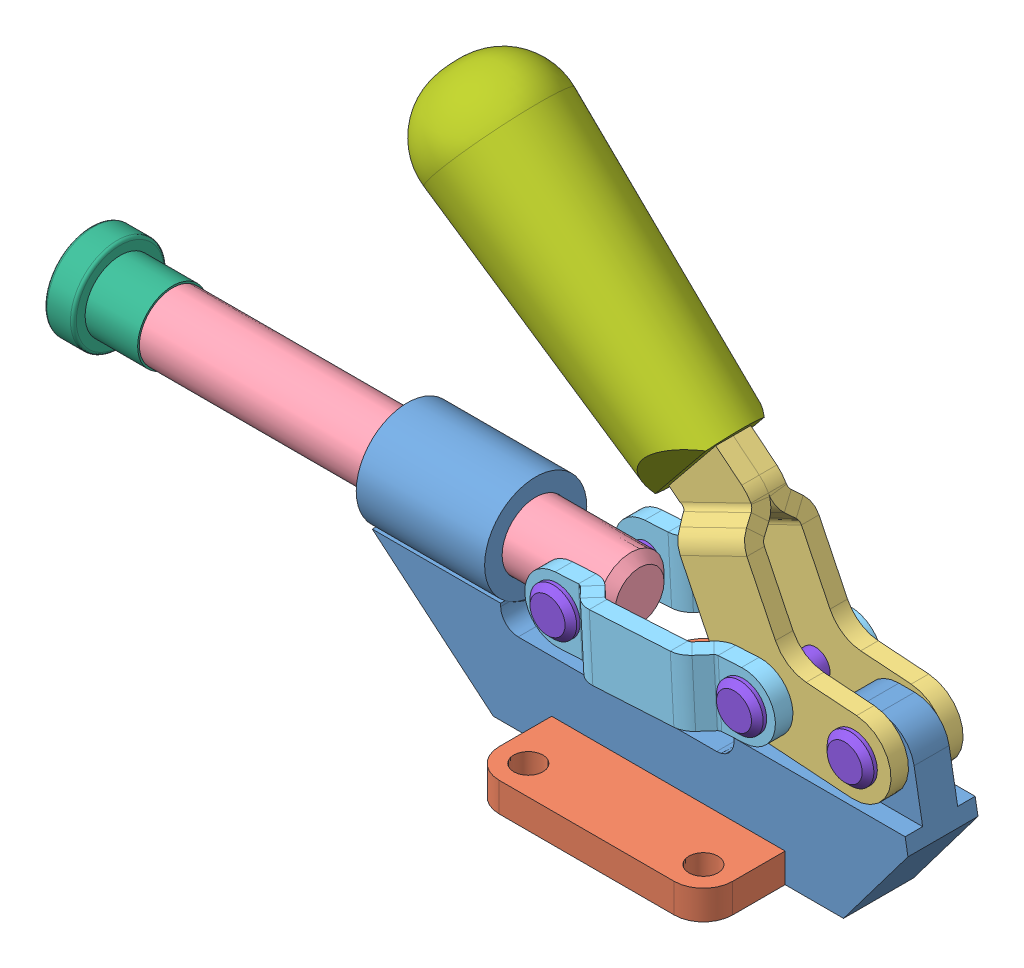
SolidWorks assembly Assem1, configuration Default. Lengths in mm.
Overall size (147.26 95.64 40).
11 component instances, 8 part files, 24 mates.
Components (placement in the parent):
- Part1-1: Part1 [Default] at origin size (91.78 33.15 17.5)
- Part6-1: Part6 [Default] at (0 5 0) size (40 5 40)
- Part2-1: Part2 [Default] at (31.9743 25.058 0) x (-0.997513 0.070487 0) z (-0.070487 -0.997513 0) size (83.44 12.35 63.32)
- Part5-1: Part5 [Default] at (-10.936 24.4 0) x (0 -1 0) z (0 0 -1) size (11.4 90 11.4)
- Part3-1: Part3 [Default] at (0.0391 25.2929 9.35) x (0.998442 0.055804 0) z (0.055804 -0.998442 0) size (43 6.17 11)
- Part3-2: Part3 [Default] at (0.0391 25.2929 -9.35) x (0.998442 0.055804 0) z (-0.055804 0.998442 0) size (43 6.17 11)
- Part7-1: Part7 [Default] at (-90.936 24.4 0) x (0 -0.381849 0.924225) z (0 -0.924225 -0.381849) size (16 14 16)
- Part4-1: Part4 [Default] at (1.0967 51.234 0) x (0 0 -1) z (-0.629889 -0.776685 0) size (21.9 57 21.9)
- clevis pin headed_iso-1: clevis pin headed_iso [ISO 2341 - B - 5 x 14 x 1.2 - St] at (31.9743 25.058 7.775) x (0 0 -1) z (1 0 0) size (15.6 8 8)
- clevis pin headed_iso-2: clevis pin headed_iso [ISO 2341 - B - 5 x 20 x 1.2 - St] at (16.0141 26.1857 10.775) x (0 0 -1) z (-0.6149 -0.788605 0) size (21.6 8 8)
- clevis pin headed_iso-3: clevis pin headed_iso [ISO 2341 - B - 5 x 20 x 1.2 - St] at (-15.936 24.4 10.775) x (0 0 -1) z (1 0 0) size (21.6 8 8)
Mates (geometry in assembly coordinates):
- Width1: width anti-aligned: plane of Part6-1 through (-15 0 20) normal (0 0 1); plane of Part6-1 through (-15 0 -20) normal (0 0 -1); plane of Part1-1 through (0 0 -6) normal (0 0 -1); plane of Part1-1 through (0 0 6) normal (0 0 1)
- Coincident1: coincident anti-aligned: plane of Part1-1 through (0 5 6) normal (0 -1 0); plane of Part6-1 through (15 5 15) normal (0 1 0)
- Coincident2: coincident anti-aligned: plane of Part1-1 through (-20 0 6) normal (1 0 0); plane of Part6-1 through (-20 0 15) normal (-1 0 0)
- Concentric1: concentric aligned: cylinder of Part1-1 through (31.9743 25.058 3) axis (0 0 -1) radius 2.5; cylinder of Part2-1 through (31.9743 25.058 6.175) axis (0 0 -1) radius 2.5
- Width2: width anti-aligned: plane of Part2-1 through (31.5117 26.0083 3.175) normal (0 0 -1); plane of Part2-1 through (31.5117 26.0083 -3.175) normal (0 0 1); plane of Part1-1 through (0 0 3) normal (0 0 1); plane of Part1-1 through (0 0 -3) normal (0 0 -1)
- Concentric2: concentric aligned: cylinder of Part1-1 through (-50.7365 24.4 0) axis (1 0 0) radius 5.75; cylinder of Part5-1 through (-100.936 24.4 0) axis (1 0 0) radius 5.7
- Concentric7: concentric aligned: cylinder of Part2-1 through (16.0141 26.1857 6.175) axis (0 0 -1) radius 2.5; cylinder of Part3-1 through (16.0141 26.1857 9.175) axis (0 0 -1) radius 2.5
- Coincident5: coincident anti-aligned: plane of Part2-1 through (31.5117 26.0083 6.175) normal (0 0 1); plane of Part3-1 through (-17.0569 24.3374 6.175) normal (0 0 -1)
- Concentric8: concentric aligned: cylinder of Part5-1 through (-15.936 24.4 10) axis (0 0 -1) radius 2.5; cylinder of Part3-1 through (-15.936 24.4 9.175) axis (0 0 -1) radius 2.5
- Concentric9: concentric aligned: cylinder of Part2-1 through (16.0141 26.1857 -6.175) axis (0 0 1) radius 2.5; cylinder of Part3-2 through (16.0141 26.1857 -9.175) axis (0 0 1) radius 2.5
- Coincident6: coincident anti-aligned: plane of Part2-1 through (31.5117 26.0083 -6.175) normal (0 0 -1); plane of Part3-2 through (-17.0569 24.3374 -6.175) normal (0 0 1)
- Concentric10: concentric anti-aligned: cylinder of Part5-1 through (-15.936 24.4 10) axis (0 0 -1) radius 2.5; cylinder of Part3-2 through (-15.936 24.4 -9.175) axis (0 0 1) radius 2.5
- Concentric11: concentric aligned: cylinder of Part5-1 through (-100.936 24.4 0) axis (1 0 0) radius 5.7; cylinder of Part7-1 through (-90.936 24.4 0) axis (1 0 0) radius 6
- Coincident7: coincident anti-aligned: plane of Part5-1 through (-100.936 24.4 0) normal (-1 0 0); plane of Part7-1 through (-100.936 24.4 0) normal (1 0 0)
- LimitAngle1: limit planar angle = 0.070545 rad anti-aligned: plane of Part1-1 through (0 17.4 6) normal (0 1 0); plane of Part2-1 through (11.9095 20.1099 6.175) normal (-0.070487 -0.997513 0)
- Width4: width anti-aligned: plane of Part4-1 through (5.065 56.1271 3) normal (-0.629889 -0.776685 0); plane of Part4-1 through (-2.8716 46.3408 3) normal (0.629889 0.776685 0); plane of Part2-1 through (10.6643 51.6821 -3) normal (0.629889 0.776685 0); plane of Part2-1 through (0.5289 43.4869 -3) normal (-0.629889 -0.776685 0)
- Concentric14: concentric aligned: circle of Part2-1; cylinder of Part4-1 through (-35.001 80.5091 3) axis (0 0 -1) radius 6.3
- Coincident13: coincident anti-aligned: plane of Part2-1 through (31.9743 25.058 -3) normal (0 0 -1); plane of Part4-1 through (-35.001 80.5091 -3) normal (0 0 1)
- Concentric15: concentric anti-aligned: cylinder of Part2-1 through (31.9743 25.058 6.175) axis (0 0 -1) radius 2.5; cylinder of clevis pin headed_iso-1 through (31.9743 25.058 7.775) axis (0 0 1) radius 4
- Coincident14: coincident anti-aligned: plane of Part2-1 through (31.5117 26.0083 6.175) normal (0 0 1); plane of clevis pin headed_iso-1 through (31.9743 29.058 6.175) normal (0 0 -1)
- Concentric16: concentric anti-aligned: cylinder of Part3-1 through (16.0141 26.1857 9.175) axis (0 0 -1) radius 2.5; cylinder of clevis pin headed_iso-2 through (16.0141 26.1857 10.775) axis (0 0 1) radius 4
- Coincident15: coincident anti-aligned: plane of Part3-1 through (-17.0569 24.3374 9.175) normal (0 0 1); plane of clevis pin headed_iso-2 through (19.1685 23.7261 9.175) normal (0 0 -1)
- Concentric17: concentric anti-aligned: cylinder of Part3-1 through (-15.936 24.4 9.175) axis (0 0 -1) radius 2.5; cylinder of clevis pin headed_iso-3 through (-15.936 24.4 10.775) axis (0 0 1) radius 4
- Coincident16: coincident anti-aligned: plane of Part3-1 through (-14.8151 24.4626 9.175) normal (0 0 1); plane of clevis pin headed_iso-3 through (-15.936 28.4 9.175) normal (0 0 -1)
